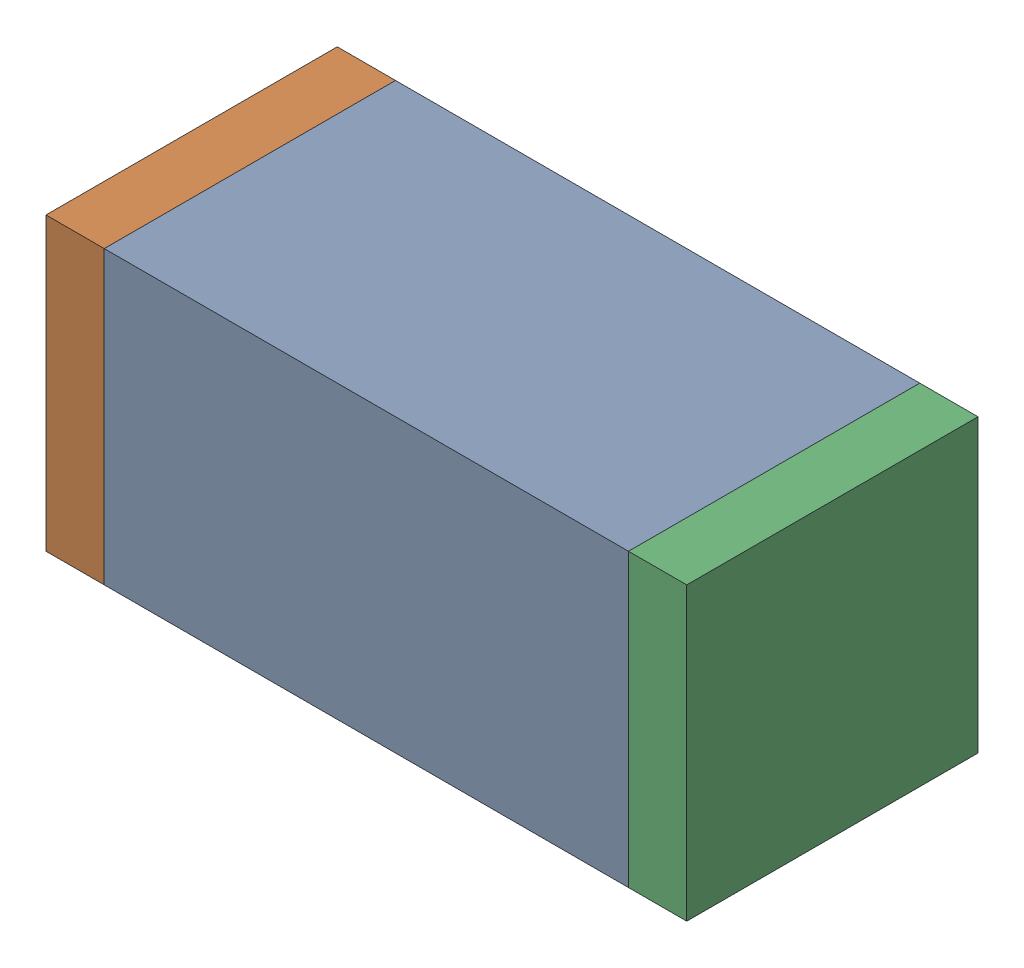
SolidWorks assembly C76, configuration Default. Lengths in mm.
Overall size (1.1 0.5 0.5).
6 component instances, 2 part files, 0 mates.
Components (placement in the parent):
- 836749680-1: 836749680 [Default] at (123.85 59.95 0) size (0.9 0.5 0.5)
  - Extruded_4-1: Extruded_4 [Default] at origin size (0.9 0.5 0.5)
- 810156080-1: 810156080 [Default] at (123.35 59.95 0) size (0.1 0.5 0.5)
  - Extruded_5-1: Extruded_5 [Default] at origin size (0.1 0.5 0.5)
- 810156080-2: 810156080 [Default] at (124.35 59.95 0) size (0.1 0.5 0.5)
  - Extruded_5-1: Extruded_5 [Default] at origin size (0.1 0.5 0.5)
